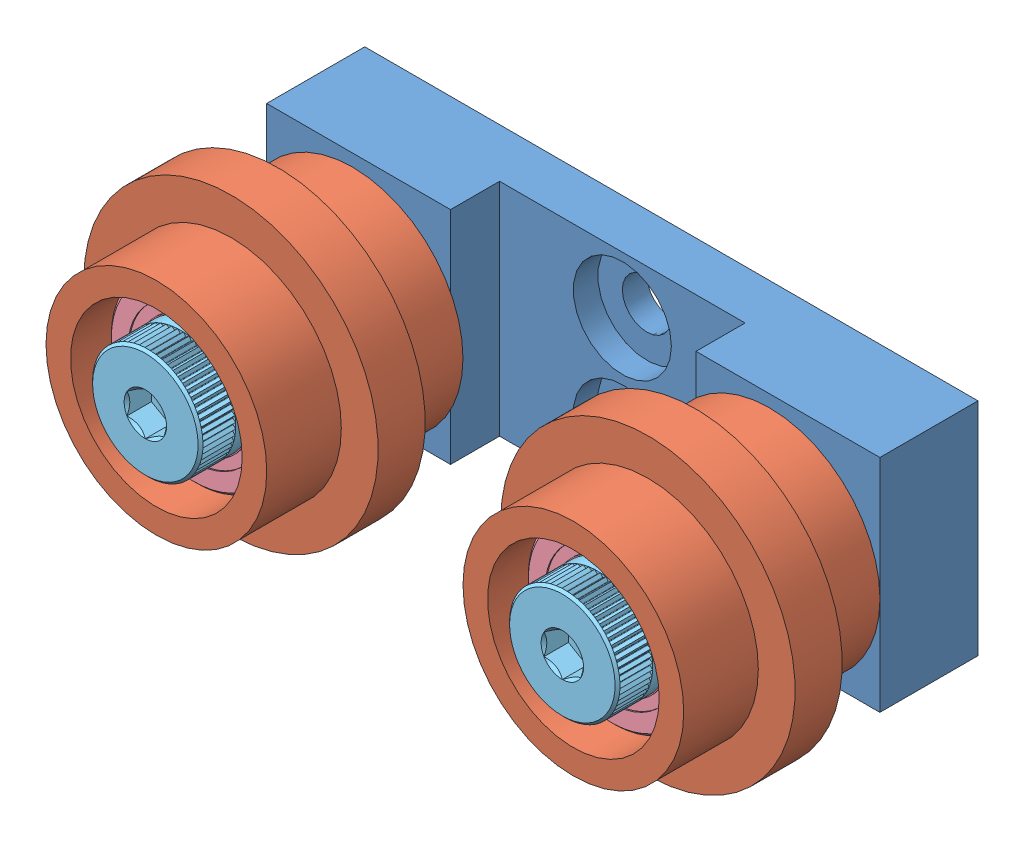
SolidWorks assembly 2018-506-A, configuration Default. Lengths in mm.
Overall size (92.08 38.1 41.78).
11 component instances, 5 part files, 32 mates.
Components (placement in the parent):
- 2018-506-D001-1: 2018-506-D001 [Default] at origin size (79.38 28.57 12.7)
- 2018-505-D002-1: 2018-505-D002 [Default] at (-26.9875 14.2875 14.2748) x (-1 0 0) z (0 0 -1) size (38.1 38.1 25.4)
- 2018-505-D002-2: 2018-505-D002 [Default] at (26.9875 14.2875 14.2748) x (-1 0 0) z (0 0 -1) size (38.1 38.1 25.4)
- 2018-505-D003-1: 2018-505-D003 [Default] at (-26.9875 14.2875 12.7) x (1 0 0) z (0 -1 0) size (22.23 1.57 22.23)
- 2018-505-D003-2: 2018-505-D003 [Default] at (26.9875 14.2875 12.7) x (1 0 0) z (0 -1 0) size (22.23 1.57 22.23)
- 2018-505-D004-1: 2018-505-D004 [60355K45] at (26.9875 14.2875 17.8149) x (1 0 0) z (0 0 -1) size (22.23 22.23 7.14)
- 2018-505-D004-2: 2018-505-D004 [60355K45] at (26.9875 14.2875 31.1817) x (1 0 0) z (0 0 -1) size (22.23 22.23 7.14)
- 2018-505-D004-3: 2018-505-D004 [60355K45] at (-26.9875 14.2875 17.8149) x (-1 0 0) z (0 0 -1) size (22.23 22.23 7.14)
- 2018-505-D004-4: 2018-505-D004 [60355K45] at (-26.9875 14.2875 31.1817) x (-1 0 0) z (0 0 -1) size (22.23 22.23 7.14)
- 2018-505-D005-1: 2018-505-D005 [91259A623] at (-26.9875 14.2875 34.7536) x (-1 0 0) z (0 1 0) size (14.29 41.78 14.29)
- 2018-505-D005-2: 2018-505-D005 [91259A623] at (26.9875 14.2875 34.7536) x (-1 0 0) z (0 1 0) size (14.29 41.78 14.29)
Mates (geometry in assembly coordinates):
- Coincident1: coordinate: point of 2018-506-D001-1; point of assembly
- Concentric1: concentric anti-aligned: cylinder of 2018-506-D001-1 through (-26.9875 14.2875 12.7) axis (0 0 1) radius 3.2639; cylinder of 2018-505-D003-1 through (-26.9875 14.2875 14.2748) axis (0 0 -1) radius 4.9784
- Coincident2: coincident anti-aligned: plane of 2018-506-D001-1 through (-15.8877 28.575 12.7) normal (0 0 1); plane of 2018-505-D003-1 through (-26.9875 14.2875 12.7) normal (0 0 -1)
- Concentric2: concentric anti-aligned: cylinder of 2018-506-D001-1 through (26.9875 14.2875 12.7) axis (0 0 1) radius 3.2639; cylinder of 2018-505-D003-2 through (26.9875 14.2875 14.2748) axis (0 0 -1) radius 4.9784
- Coincident3: coincident anti-aligned: plane of 2018-506-D001-1 through (39.6875 28.575 12.7) normal (0 0 1); plane of 2018-505-D003-2 through (26.9875 14.2875 12.7) normal (0 0 -1)
- Concentric3: concentric aligned: cylinder of 2018-505-D002-2 through (26.9875 14.2875 21.3868) axis (0 0 -1) radius 11.1125; cylinder of 2018-505-D004-1 through (26.9875 14.2875 14.2431) axis (0 0 -1) radius 4.7625
- Coincident4: coincident anti-aligned: plane of 2018-505-D002-2 through (26.9875 14.2875 21.3868) normal (0 0 -1); plane of 2018-505-D004-1 through (28.9486 9.5583 21.3868) normal (0 0 1)
- Concentric4: concentric anti-aligned: cylinder of 2018-505-D002-2 through (26.9875 14.2875 27.6098) axis (0 0 1) radius 11.1125; cylinder of 2018-505-D004-2 through (26.9875 14.2875 27.6098) axis (0 0 -1) radius 4.7625
- Coincident5: coincident anti-aligned: plane of 2018-505-D002-2 through (26.9875 14.2875 27.6098) normal (0 0 1); plane of 2018-505-D004-2 through (26.9875 3.5322 27.6098) normal (0 0 -1)
- Concentric5: concentric aligned: cylinder of 2018-505-D002-1 through (-26.9875 14.2875 21.3868) axis (0 0 -1) radius 11.1125; cylinder of 2018-505-D004-3 through (-26.9875 14.2875 14.2431) axis (0 0 -1) radius 11.1125
- Coincident6: coincident anti-aligned: plane of 2018-505-D002-1 through (-26.9875 14.2875 21.3868) normal (0 0 -1); plane of 2018-505-D004-3 through (-31.1073 24.2225 21.3868) normal (0 0 1)
- Concentric6: concentric anti-aligned: cylinder of 2018-505-D002-1 through (-26.9875 14.2875 27.6098) axis (0 0 1) radius 11.1125; cylinder of 2018-505-D004-4 through (-26.9875 14.2875 27.6098) axis (0 0 -1) radius 4.7625
- Coincident7: coincident anti-aligned: plane of 2018-505-D002-1 through (-26.9875 14.2875 27.6098) normal (0 0 1); plane of 2018-505-D004-4 through (-31.1073 24.2225 27.6098) normal (0 0 -1)
- Concentric7: concentric anti-aligned: cylinder of 2018-506-D001-1 through (-26.9875 14.2875 12.7) axis (0 0 1) radius 3.2639; cylinder of 2018-505-D004-3 through (-26.9875 14.2875 14.2431) axis (0 0 -1) radius 4.7625
- Coincident8: coincident anti-aligned: plane of 2018-505-D002-1 through (-26.9875 14.2875 14.2748) normal (0 0 -1); plane of 2018-505-D003-1 through (-26.9875 14.2875 14.2748) normal (0 0 1)
- Concentric8: concentric anti-aligned: cylinder of 2018-506-D001-1 through (26.9875 14.2875 12.7) axis (0 0 1) radius 3.2639; cylinder of 2018-505-D004-1 through (26.9875 14.2875 14.2431) axis (0 0 -1) radius 4.7625
- Coincident9: coincident aligned: plane of 2018-505-D002-1 through (-26.9875 28.575 39.6748) normal (0 0 1); plane of 2018-505-D002-2 through (26.9875 28.575 39.6748) normal (0 0 1)
- Concentric9: concentric aligned: cylinder of 2018-505-D004-4 through (-26.9875 14.2875 27.6098) axis (0 0 -1) radius 4.7625; cylinder of 2018-505-D005-1 through (-26.9875 14.2875 34.7536) axis (0 0 -1) radius 4.7625
- Coincident10: coincident anti-aligned: plane of 2018-505-D004-4 through (-28.9486 19.0167 34.7536) normal (0 0 1); plane of 2018-505-D005-1 through (-26.9875 14.2875 34.7536) normal (0 0 -1)
- Concentric10: concentric aligned: cylinder of 2018-505-D004-2 through (26.9875 14.2875 27.6098) axis (0 0 -1) radius 4.7625; cylinder of 2018-505-D005-2 through (26.9875 14.2875 34.7536) axis (0 0 -1) radius 4.7625
- Coincident11: coincident anti-aligned: plane of 2018-505-D004-2 through (26.9875 9.1678 34.7536) normal (0 0 1); plane of 2018-505-D005-2 through (26.9875 14.2875 34.7536) normal (0 0 -1)
- Parallel1: parallel aligned: plane of 2018-505-D002-1 through (-26.9875 14.2875 14.2748) normal (0 1 0); plane of assembly
- Parallel2: parallel aligned: plane of 2018-505-D002-1 through (-26.9875 14.2875 14.2748) normal (0 1 0); plane of assembly
- Parallel3: parallel aligned: plane of 2018-505-D002-2 through (26.9875 14.2875 14.2748) normal (0 1 0); plane of assembly
- Parallel4: parallel anti-aligned: plane of 2018-505-D003-1 through (-26.9875 14.2875 12.7) normal (0 -1 0); plane of assembly
- Parallel5: parallel anti-aligned: plane of 2018-505-D003-2 through (26.9875 14.2875 12.7) normal (0 -1 0); plane of assembly
- Parallel6: parallel anti-aligned: plane of 2018-505-D004-1 through (26.9875 14.2875 17.8149) normal (0 -1 0); plane of assembly
- Parallel7: parallel anti-aligned: plane of 2018-505-D004-2 through (26.9875 14.2875 31.1817) normal (0 -1 0); plane of assembly
- Parallel8: parallel aligned: plane of 2018-505-D004-3 through (-26.9875 14.2875 17.8149) normal (0 1 0); plane of assembly
- Parallel9: parallel aligned: plane of 2018-505-D005-2 through (26.9875 14.2875 34.7536) normal (0 1 0); plane of assembly
- Parallel10: parallel aligned: plane of 2018-505-D005-1 through (-26.9875 14.2875 34.7536) normal (0 1 0); plane of assembly
- Parallel11: parallel aligned: plane of 2018-505-D004-4 through (-26.9875 14.2875 31.1817) normal (0 1 0); plane of assembly
